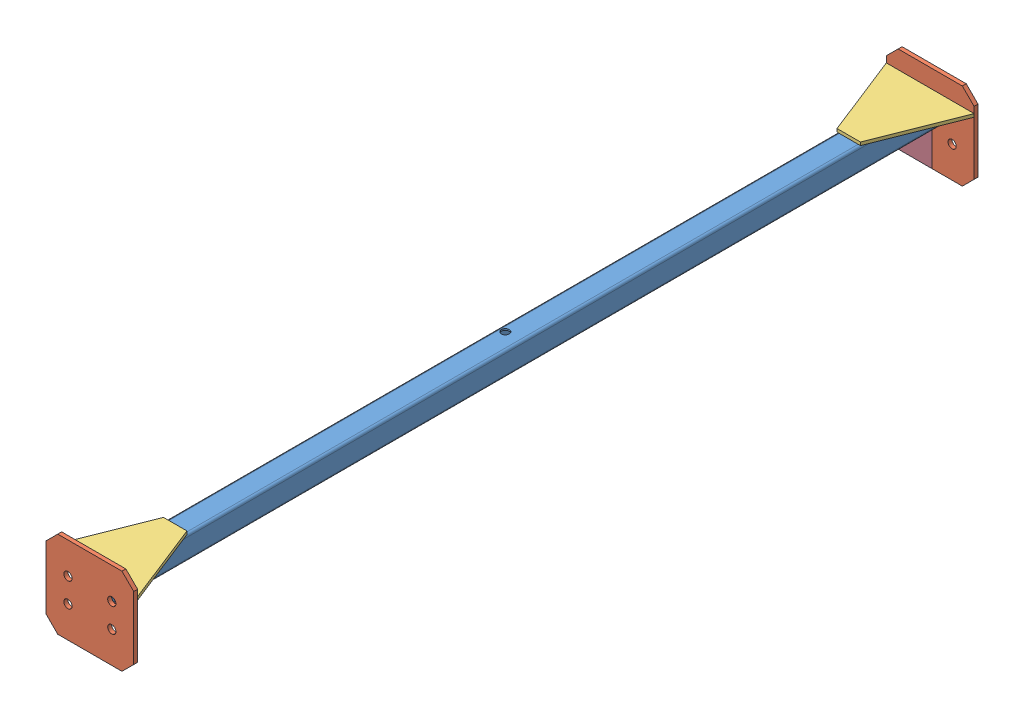
SolidWorks assembly ТП.016.01.01.01.01.00 - Поперечная балка в сборе, configuration Центральная. Lengths in mm.
Overall size (112 110.77 1078).
11 component instances, 6 part files, 30 mates.
Components (placement in the parent):
- ТП.016.01.01.01.01.01 - Поперечная балка (30х30)-1: ТП.016.01.01.01.01.01 - Поперечная балка (30х30) [--] at origin size (30 30 1068)
- ТП.016.01.01.01.01.02 - Пластина кронштейна (5мм)-1: ТП.016.01.01.01.01.02 - Пластина кронштейна (5мм) [--] at (0 -56.7738 -5) size (112 110.77 5)
- ТП.016.01.01.01.01.03 - Косынка верхняя (4мм)-1: ТП.016.01.01.01.01.03 - Косынка верхняя (4мм) [--] at (0 30 -10) size (112 4 104)
- ТП.016.01.01.01.01.02 - Пластина кронштейна (5мм)-2: ТП.016.01.01.01.01.02 - Пластина кронштейна (5мм) [--] at (0 -56.7738 -1083) x (-1 0 0) z (0 0 -1) size (112 110.77 5)
- ТП.016.01.01.01.01.03 - Косынка верхняя (4мм)-2: ТП.016.01.01.01.01.03 - Косынка верхняя (4мм) [--] at (0 30 -1078) x (-1 0 0) z (0 0 -1) size (112 4 104)
- ТП.016.01.01.01.01.04 - Косынка нижняя (4мм)-2: ТП.016.01.01.01.01.04 - Косынка нижняя (4мм) [--] at (0 0 -1078) x (-1 0 0) z (0 0 -1) size (4 53.77 53.77)
- ТП.016.01.01.01.01.04 - Косынка нижняя (4мм)-3: ТП.016.01.01.01.01.04 - Косынка нижняя (4мм) [--] at (0 0 -10) size (4 53.77 53.77)
- ТП.016.01.01.01.01.05 - Пластина кронштейна задняя (5мм)-1: ТП.016.01.01.01.01.05 - Пластина кронштейна задняя (5мм) [--] at (0 -56.7738 -1083) x (-1 0 0) z (0 0 -1) size (112 110.77 5) (hidden)
- ТП.016.01.01.01.01.06 - Косынка верхняя задняя (4мм)-1: ТП.016.01.01.01.01.06 - Косынка верхняя задняя (4мм) [--] at (-15 30 -1078) x (-1 0 0) z (0 0 -1) size (111.99 4 104) (hidden)
- ТП.016.01.01.01.01.05 - Пластина кронштейна задняя (5мм)-2: ТП.016.01.01.01.01.05 - Пластина кронштейна задняя (5мм) [--] at (0 -56.7738 -10) x (-1 0 0) z (0 0 -1) size (112 110.77 5) (hidden)
- ТП.016.01.01.01.01.06 - Косынка верхняя задняя (4мм)-2: ТП.016.01.01.01.01.06 - Косынка верхняя задняя (4мм) [--] at (-15 34 -10) x (-1 0 0) z (0 0 1) size (111.99 4 104) (hidden)
Mates (geometry in assembly coordinates):
- Совпадение1: coincident: plane of ТП.016.01.01.01.01.01 - Поперечная балка (30х30)-1 through (12 0 -1036.4264) normal (0 -1 0); plane of ТП.016.01.01.01.01.04 - Косынка нижняя (4мм)-3 through (-2 0 -63.7738) normal (0 1 0)
- Совпадение2: coincident: plane of ТП.016.01.01.01.01.01 - Поперечная балка (30х30)-1 through (12 30 -1036.4264) normal (0 1 0); plane of ТП.016.01.01.01.01.03 - Косынка верхняя (4мм)-1 through (0 30 -10) normal (0 -1 0)
- Совпадение3: coincident: plane of ТП.016.01.01.01.01.01 - Поперечная балка (30х30)-1 through (12 27 -10) normal (0 0 1); plane of ТП.016.01.01.01.01.02 - Пластина кронштейна (5мм)-1 through (0 -56.7738 -10) normal (0 0 -1)
- Совпадение4: coincident: plane of ТП.016.01.01.01.01.02 - Пластина кронштейна (5мм)-1 through (0 -56.7738 -10) normal (0 0 -1); plane of ТП.016.01.01.01.01.03 - Косынка верхняя (4мм)-1 through (-56 34 -10) normal (0 0 1)
- Совпадение5: coincident: plane of ТП.016.01.01.01.01.02 - Пластина кронштейна (5мм)-1 through (0 -56.7738 -10) normal (0 0 -1); plane of ТП.016.01.01.01.01.04 - Косынка нижняя (4мм)-3 through (-2 0 -10) normal (0 0 1)
- Совпадение6: coincident: line of ТП.016.01.01.01.01.02 - Пластина кронштейна (5мм)-1 through (-41 -53.7738 -10) axis (1 0 0); line of ТП.016.01.01.01.01.04 - Косынка нижняя (4мм)-3 through (2 -53.7738 -10) axis (-1 0 0)
- Совпадение7: coincident: line of ТП.016.01.01.01.01.02 - Пластина кронштейна (5мм)-1 through (56 -38.7738 -10) axis (0 1 0); line of ТП.016.01.01.01.01.03 - Косынка верхняя (4мм)-1 through (56 34 -10) axis (0 -1 0)
- Совпадение8: coincident: plane of ТП.016.01.01.01.01.04 - Косынка нижняя (4мм)-3 through (0 0 -10) normal (1 0 0); point of assembly
- Совпадение9: coincident: plane of ТП.016.01.01.01.01.01 - Поперечная балка (30х30)-1 through (15 3 -1036.4264) normal (1 0 0); line of ТП.016.01.01.01.01.03 - Косынка верхняя (4мм)-1 through (15 34 -114) axis (0 -1 0)
- Совпадение10: coincident: plane of ТП.016.01.01.01.01.03 - Косынка верхняя (4мм)-2 through (56 34 -1078) normal (0 0 -1); plane of ТП.016.01.01.01.01.02 - Пластина кронштейна (5мм)-2 through (0 -56.7738 -1078) normal (0 0 1)
- Совпадение11: coincident: plane of ТП.016.01.01.01.01.02 - Пластина кронштейна (5мм)-2 through (0 -56.7738 -1078) normal (0 0 1); plane of ТП.016.01.01.01.01.04 - Косынка нижняя (4мм)-2 through (2 0 -1078) normal (0 0 -1)
- Совпадение12: coincident: line of ТП.016.01.01.01.01.02 - Пластина кронштейна (5мм)-2 through (41 -53.7738 -1078) axis (-1 0 0); line of ТП.016.01.01.01.01.04 - Косынка нижняя (4мм)-2 through (-2 -53.7738 -1078) axis (1 0 0)
- Совпадение13: coincident: line of ТП.016.01.01.01.01.03 - Косынка верхняя (4мм)-2 through (-56 34 -1078) axis (0 -1 0); line of ТП.016.01.01.01.01.02 - Пластина кронштейна (5мм)-2 through (-56 -38.7738 -1078) axis (0 1 0)
- Совпадение14: coincident: plane of ТП.016.01.01.01.01.01 - Поперечная балка (30х30)-1 through (12 0 -1036.4264) normal (0 -1 0); plane of ТП.016.01.01.01.01.04 - Косынка нижняя (4мм)-2 through (2 0 -1024.2262) normal (0 1 0)
- Совпадение15: coincident: plane of ТП.016.01.01.01.01.01 - Поперечная балка (30х30)-1 through (12 30 -1036.4264) normal (0 1 0); plane of ТП.016.01.01.01.01.03 - Косынка верхняя (4мм)-2 through (0 30 -1078) normal (0 -1 0)
- Совпадение16: coincident: plane of ТП.016.01.01.01.01.01 - Поперечная балка (30х30)-1 through (12 27 -1078) normal (0 0 -1); plane of ТП.016.01.01.01.01.02 - Пластина кронштейна (5мм)-2 through (0 -56.7738 -1078) normal (0 0 1)
- Совпадение17: coincident: plane of ТП.016.01.01.01.01.01 - Поперечная балка (30х30)-1 through (-15 3 -1036.4264) normal (-1 0 0); line of ТП.016.01.01.01.01.03 - Косынка верхняя (4мм)-2 through (-15 34 -974) axis (0 -1 0)
- Совпадение18: coincident: plane of ТП.016.01.01.01.01.04 - Косынка нижняя (4мм)-2 through (0 0 -1078) normal (-1 0 0); point of assembly
- Совпадение19: coincident: plane of ТП.016.01.01.01.01.01 - Поперечная балка (30х30)-1 through (12 27 -1078) normal (0 0 -1); plane of ТП.016.01.01.01.01.05 - Пластина кронштейна задняя (5мм)-1 through (0 -56.7738 -1078) normal (0 0 1)
- Совпадение20: coincident: line of ТП.016.01.01.01.01.04 - Косынка нижняя (4мм)-2 through (-2 -53.7738 -1078) axis (1 0 0); line of ТП.016.01.01.01.01.05 - Пластина кронштейна задняя (5мм)-1 through (41 -53.7738 -1078) axis (-1 0 0)
- Совпадение21: coincident: plane of ТП.016.01.01.01.01.01 - Поперечная балка (30х30)-1 through (12 30 -1036.4264) normal (0 1 0); plane of ТП.016.01.01.01.01.06 - Косынка верхняя задняя (4мм)-1 through (-15 30 -1078) normal (0 -1 0)
- Совпадение22: coincident: plane of ТП.016.01.01.01.01.05 - Пластина кронштейна задняя (5мм)-1 through (0 -56.7738 -1078) normal (0 0 1); plane of ТП.016.01.01.01.01.06 - Косынка верхняя задняя (4мм)-1 through (-56 34 -1078) normal (0 0 -1)
- Совпадение23: coincident: line of ТП.016.01.01.01.01.05 - Пластина кронштейна задняя (5мм)-1 through (-56 -38.7738 -1078) axis (0 1 0); line of ТП.016.01.01.01.01.06 - Косынка верхняя задняя (4мм)-1 through (-56 34 -1078) axis (0 -1 0)
- Совпадение24: coincident: plane of ТП.016.01.01.01.01.01 - Поперечная балка (30х30)-1 through (-15 3 -1036.4264) normal (-1 0 0); line of ТП.016.01.01.01.01.06 - Косынка верхняя задняя (4мм)-1 through (-15 34 -974) axis (0 -1 0)
- Совпадение25: coincident: plane of ТП.016.01.01.01.01.01 - Поперечная балка (30х30)-1 through (12 27 -10) normal (0 0 1); plane of ТП.016.01.01.01.01.05 - Пластина кронштейна задняя (5мм)-2 through (0 -56.7738 -10) normal (0 0 -1)
- Совпадение26: coincident: plane of ТП.016.01.01.01.01.01 - Поперечная балка (30х30)-1 through (12 30 -1036.4264) normal (0 1 0); plane of ТП.016.01.01.01.01.06 - Косынка верхняя задняя (4мм)-2 through (-15 30 -10) normal (0 -1 0)
- Совпадение27: coincident: plane of ТП.016.01.01.01.01.05 - Пластина кронштейна задняя (5мм)-2 through (0 -56.7738 -10) normal (0 0 -1); plane of ТП.016.01.01.01.01.06 - Косынка верхняя задняя (4мм)-2 through (-56 30 -10) normal (0 0 1)
- Совпадение28: coincident: plane of ТП.016.01.01.01.01.01 - Поперечная балка (30х30)-1 through (-15 3 -1036.4264) normal (-1 0 0); line of ТП.016.01.01.01.01.06 - Косынка верхняя задняя (4мм)-2 through (-15 30 -114) axis (0 1 0)
- Совпадение29: coincident: line of ТП.016.01.01.01.01.05 - Пластина кронштейна задняя (5мм)-2 through (-56 -53.7738 -10) axis (0 1 0); line of ТП.016.01.01.01.01.06 - Косынка верхняя задняя (4мм)-2 through (-56 30 -10) axis (0 1 0)
- Совпадение30: coincident: line of ТП.016.01.01.01.01.04 - Косынка нижняя (4мм)-3 through (2 -53.7738 -10) axis (-1 0 0); line of ТП.016.01.01.01.01.05 - Пластина кронштейна задняя (5мм)-2 through (-56 -53.7738 -10) axis (1 0 0)
